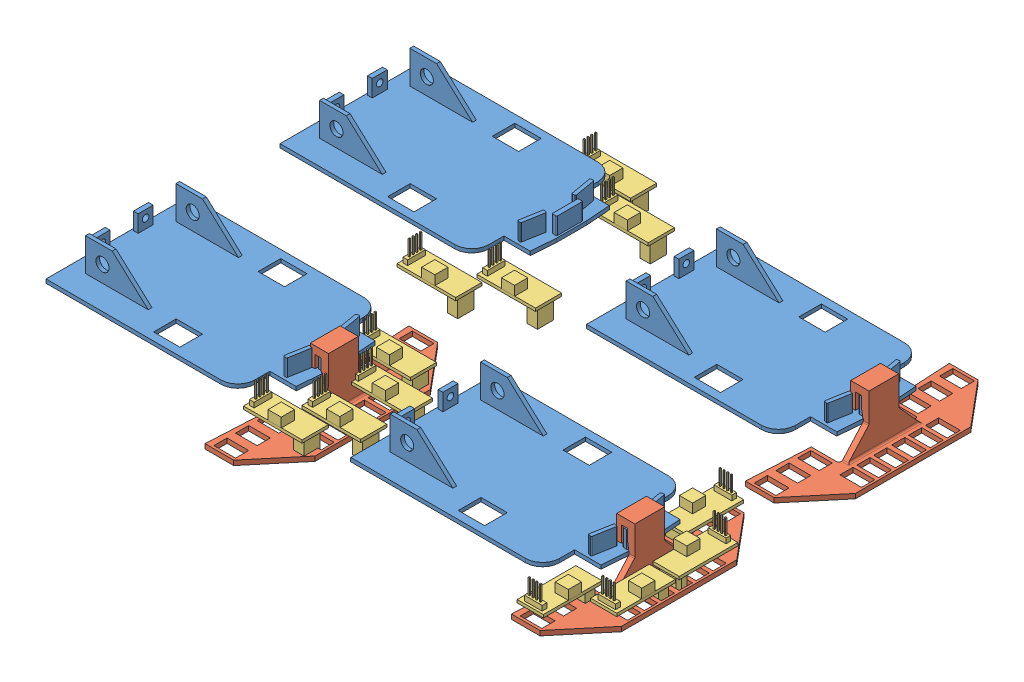
SolidWorks assembly chassis_com_encaixe, configuration Valor predeterminado. Lengths in mm.
Overall size (298.98 38.55 232.4).
25 component instances, 5 part files, 11 mates.
Components (placement in the parent):
- chassis_com_detalhes-1: chassis_com_detalhes [Valor predeterminado] at origin size (117 19.43 76)
- suporteSensor_encaixe_em_x-1: suporteSensor_encaixe_em_x [Valor predeterminado] at (126.1388 -18.0686 -0.0217) size (27 23.2 61) (hidden)
- suporteSensor_encaixe_em_z-1: suporteSensor_encaixe_em_z [Valor predeterminado] at (125.1414 -17.8795 -0.1119) size (22.7 30.5 66) (hidden)
- suporte_sensores_avulsos-1: suporte_sensores_avulsos [Valor predeterminado] at (125.1068 -17.8601 -0.0184) size (34.95 30.5 108.4)
- sensor_individual-1: sensor_individual [Valor predeterminado] at (118.4664 -7.6757 28.9559) size (31.2 22.98 14)
- sensor_individual-2: sensor_individual [Valor predeterminado] at (133.335 -8.103 12.7041) size (31.2 22.98 14)
- sensor_individual-3: sensor_individual [Valor predeterminado] at (133.521 -8.0445 -11.3825) size (31.2 22.98 14)
- sensor_individual-4: sensor_individual [Valor predeterminado] at (118.4868 -7.6947 -28.5573) size (31.2 22.98 14)
- chassis_com_detalhes-2: chassis_com_detalhes [Valor predeterminado] at (0.4379 0.5122 -124) size (117 19.43 76)
- sensor_individual-5: sensor_individual [Valor predeterminado] at (94.69 -7.5065 -169.4472) size (31.2 22.98 14)
- sensor_individual-6: sensor_individual [Valor predeterminado] at (93.9206 -7.5065 -77.2478) size (31.2 22.98 14)
- sensor_individual-7: sensor_individual [Valor predeterminado] at (120.4183 -7.0857 -93.1406) size (31.2 22.98 14)
- sensor_individual-8: sensor_individual [Valor predeterminado] at (120.1775 -7.2026 -153.3214) size (31.2 22.98 14)
- chassis_com_detalhes-3: chassis_com_detalhes [Valor predeterminado] at (162 -1.1812 0) size (117 19.43 76)
- sensor_individual-9: sensor_individual [Valor predeterminado] at (290.6771 -7.5639 16.6) x (0 0 -1) z (1 0 0) size (31.2 22.98 14)
- sensor_individual-10: sensor_individual [Valor predeterminado] at (290.6796 -7.2026 -16.6) x (0 0 1) z (-1 0 0) size (31.2 22.98 14)
- sensor_individual-11: sensor_individual [Valor predeterminado] at (272.7334 -6.6126 37.697) x (0 0 -1) z (1 0 0) size (31.2 22.98 14)
- sensor_individual-12: sensor_individual [Valor predeterminado] at (272.4824 -7.1893 -37.8825) x (0 0 1) z (-1 0 0) size (31.2 22.98 14)
- chassis_com_detalhes-4: chassis_com_detalhes [Valor predeterminado] at (163.4129 -1.1812 -124) size (117 19.43 76)
- sensor_individual-13: sensor_individual [Valor predeterminado] at (273.683 -1.0651 -86.4) x (0 0 1) z (-1 0 0) size (31.2 22.98 14) (hidden)
- sensor_individual-14: sensor_individual [Valor predeterminado] at (291.7981 -1.1712 -108.6791) x (0 0 -1) z (1 0 0) size (31.2 22.98 14) (hidden)
- sensor_individual-15: sensor_individual [Valor predeterminado] at (273.3629 -0.1712 -161.6) x (0 0 -1) z (1 0 0) size (31.2 22.98 14) (hidden)
- sensor_individual-16: sensor_individual [Valor predeterminado] at (291.4978 -0.3712 -141.7898) x (0 0 1) z (-1 0 0) size (31.2 22.98 14) (hidden)
- suporte_sensores_avulsos-2: suporte_sensores_avulsos [Valor predeterminado] at (288.424 -15.4312 -124) size (34.95 30.5 108.4)
- suporte_sensores_avulsos-3: suporte_sensores_avulsos [Valor predeterminado] at (288.0075 -14.8312 0) size (34.95 30.5 108.4)
Mates (geometry in assembly coordinates):
- Distância1: distance = 162 mm aligned: plane of chassis-3 through (162 -1.1812 0) normal (1 0 0)
- Distância3: distance = 2 mm anti-aligned: plane of sensor_individual-10 through (283.7296 -5.6226 -1) normal (0 0 1); plane of sensor_individual-9 through (297.6271 -5.9839 1) normal (0 0 -1)
- Coincidente10: coincident aligned: plane of chassis-3 through (162 -1.1812 0) normal (0 0 1)
- Simétrico1: symmetric aligned: plane of chassis-3 through (162 -1.1812 0) normal (0 0 1); plane of sensor_individual-9 through (297.6271 -5.9839 1) normal (0 0 -1); plane of sensor_individual-10 through (283.7296 -5.6226 -1) normal (0 0 1)
- Distância4: distance = 124 mm aligned: plane of chassis-2 through (0.4379 0.5122 -124) normal (0 0 1)
- Distância5: distance = 124 mm aligned: plane of chassis-4 through (163.4129 -1.1812 -124) normal (0 0 1)
- Coincidente13: coincident aligned: plane of chassis-4 through (163.4129 -1.1812 -124) normal (0 0 1); plane of suporte_sensores_avulsos-2 through (288.424 -15.4312 -124) normal (0 0 1)
- Distância7: distance = 1 mm anti-aligned: plane of sensor_individual-13 through (266.733 0.5149 -102) normal (0 0 -1); plane of chassis-4 through (279.4129 0.8188 -103) normal (0 0 1)
- Distância8: distance = 1 mm anti-aligned: plane of sensor_individual-15 through (280.3129 1.4088 -146) normal (0 0 1); plane of chassis-4 through (279.4129 0.8188 -145) normal (0 0 -1)
- Distância9: distance = 1 mm anti-aligned: plane of sensor_individual-15 through (266.4129 1.4088 -146) normal (-1 0 0); plane of chassis-4 through (265.4129 0.8188 -153) normal (1 0 0)
- Coincidente18: coincident aligned: plane of suporte_sensores_avulsos-3 through (288.0075 -14.8312 0) normal (0 0 1)
